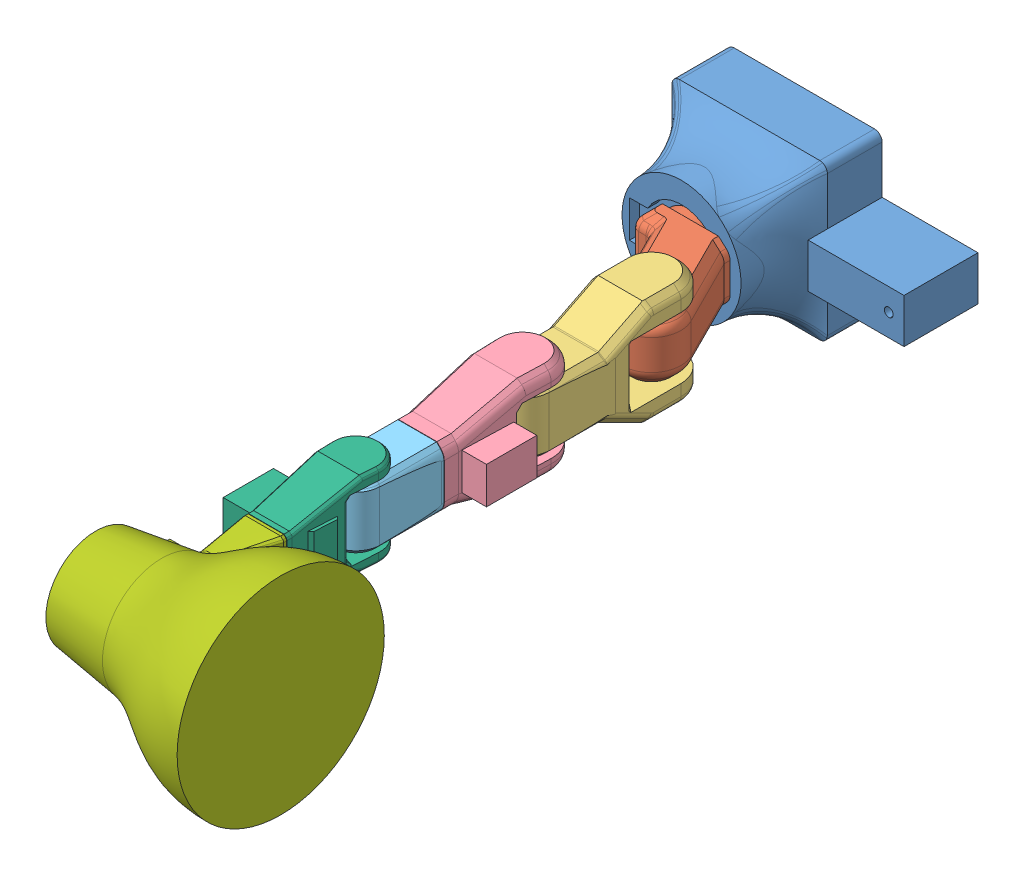
SolidWorks assembly Robot_Assem, configuration Default. Lengths in mm.
Overall size (178.46 140 549.62).
7 component instances, 7 part files, 21 mates.
Components (placement in the parent):
- base-1: base [Default] at (-12.5 0 41.45) x (0 1 0) z (-1 0 0) size (105.5 83.06 170.05)
- link1-1: link1 [Default] at (0 0 76.5) x (0 -1 0) z (-1 0 0) size (41.12 84.67 77.71)
- link2-1: link2 [Default] at (37.7067 -15.6 215.6656) x (1 0 0) z (0 0 -1) size (40.05 71.1 125.5)
- link3-1: link3 [Default] at (50.2067 -0.05 253.3656) x (0 -1 0) z (1 0 0) size (64.5 90.95 54.8)
- link4-1: link4 [Default] at (37.7067 -15.65 328.3656) x (1 0 0) z (0 0 -1) size (36.05 41.5 63.02)
- link5-1: link5 [Default] at (25.2067 -0.05 361.7156) x (0 1 0) z (-1 0 0) size (56.5 76 51.5)
- EE-1: EE [Default] at (63.2067 -0.05 479.6156) x (-1 0 0) z (0 0 -1) size (125 140 153.2)
Mates (geometry in assembly coordinates):
- Distance1: distance = 0.25 mm anti-aligned: plane of link1-1 through (0 0 76.5) normal (0 0 -1); plane of base-1 through (0 0 76.25) normal (0 0 1)
- Concentric1: concentric aligned: cylinder of base-1 through (0 0 76.25) axis (0 0 1) radius 26.05; cylinder of link1-1 through (0 0 76.5) axis (0 0 1) radius 20
- Parallel1: parallel aligned: plane of base-1 through (-52.5 -52.5 32) normal (0 -1 0); plane of link1-1 through (27.934 -20.55 123.126) normal (0 -1 0)
- Concentric2: concentric anti-aligned: cylinder of link1-1 through (37.7067 22.55 141.1656) axis (0 -1 0) radius 10.5; cylinder of link2-1 through (37.7067 -20.8 141.1656) axis (0 1 0) radius 10.25
- Distance2: distance = 0.25 mm anti-aligned: plane of link2-1 through (37.7067 -20.8 155.1656) normal (0 1 0); plane of link1-1 through (27.934 -20.55 123.126) normal (0 -1 0)
- Parallel2: parallel aligned: plane of base-1 through (-52.5 52.5 32) normal (-1 0 0); plane of link2-1 through (17.7067 -20.55 184.1656) normal (-1 0 0)
- Concentric3: concentric anti-aligned: cylinder of link2-1 through (37.7067 -22.55 228.1656) axis (0 1 0) radius 10.5; cylinder of link3-1 through (37.7067 20.7 228.1656) axis (0 -1 0) radius 10.25
- Distance3: distance = 0.25 mm anti-aligned: plane of link3-1 through (37.7067 -20.8 228.1656) normal (0 1 0); plane of link2-1 through (37.7067 -20.55 215.1656) normal (0 -1 0)
- Parallel3: parallel anti-aligned: plane of base-1 through (-52.5 52.5 32) normal (-1 0 0); plane of link3-1 through (72.5067 -0.05 286.3656) normal (1 0 0)
- Distance4: distance = 0.25 mm anti-aligned: plane of link4-1 through (37.7067 -0.05 299.3656) normal (0 0 -1); plane of link3-1 through (37.7343 -0.05 299.1156) normal (0 0 1)
- Concentric4: concentric aligned: cylinder of link3-1 through (37.7067 -0.05 287.2156) axis (0 0 -1) radius 10.5; cylinder of link4-1 through (37.7067 -0.05 299.3656) axis (0 0 -1) radius 7.5
- Parallel4: parallel aligned: plane of link3-1 through (24.7092 -20.8 290.2156) normal (0 -1 0); plane of link4-1 through (37.7067 -20.8 329.8656) normal (0 -1 0)
- Concentric5: concentric aligned: cylinder of link4-1 through (37.7067 -22.6 340.8656) axis (0 1 0) radius 10.5; cylinder of link5-1 through (37.7067 -21.05 340.8656) axis (0 1 0) radius 10.25
- Distance5: distance = 0.25 mm anti-aligned: plane of link5-1 through (37.7067 20.95 354.2656) normal (0 -1 0); plane of link4-1 through (37.7067 20.7 329.8656) normal (0 1 0)
- Parallel5: parallel aligned: plane of base-1 through (-52.5 52.5 32) normal (-1 0 0); plane of link5-1 through (2.9067 -0.05 394.7156) normal (-1 0 0)
- Distance6: distance = 0.25 mm anti-aligned: plane of EE-1 through (36.7063 -0.05 400.6156) normal (0 0 -1); plane of link5-1 through (36.7065 -0.05 400.3656) normal (0 0 1)
- Concentric6: concentric aligned: cylinder of link5-1 through (37.7067 -0.05 400.3656) axis (0 0 -1) radius 7.5; cylinder of EE-1 through (37.7067 -0.05 428.8999) axis (0 0 -1) radius 5
- Parallel6: parallel aligned: plane of base-1 through (-52.5 52.5 32) normal (-1 0 0); plane of EE-1 through (0.7067 -0.05 445.8784) normal (-1 0 0)
- Coincident1: coincident anti-aligned: plane of base-1 through (0 0 0) normal (0 0 -1); plane of assembly through (0 0 0) normal (0 0 1)
- Distance7: distance = 12.5 mm anti-aligned: plane of base-1 through (-12.5 0 41.45) normal (-1 0 0); plane of assembly through (0 0 0) normal (1 0 0)
- Coincident3: coincident aligned: plane of base-1; plane of assembly through (0 0 0) normal (0 1 0)
